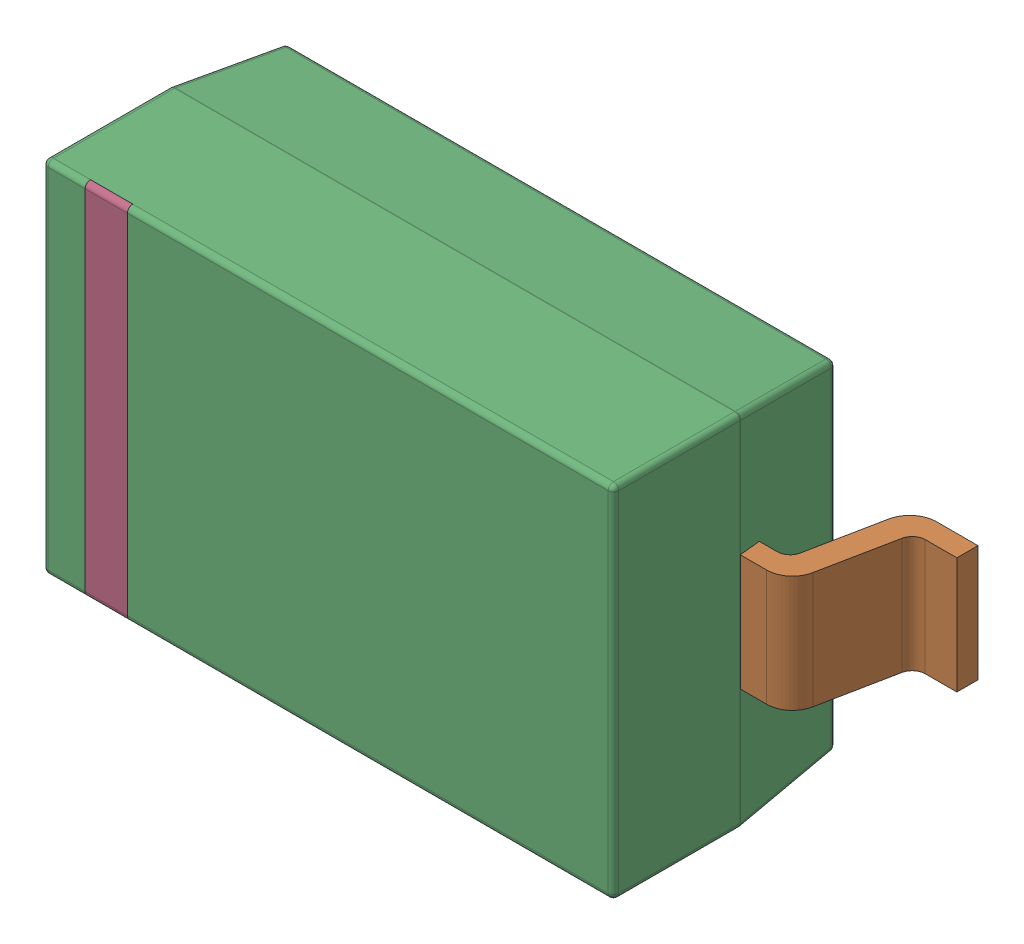
SolidWorks assembly D6, configuration Default. Lengths in mm.
Overall size (3.75 1.71 1.2).
5 component instances, 4 part files, 0 mates.
Components (placement in the parent):
- sod123_v4-1: sod123_v4 [Default] at (75.4701 4.8401 0) x (1 0 0) z (0 0 1) size (3.75 1.71 1.2)
  - pin-1: pin [Default] at (-0.675 -0.875 0) x (0 -1 0) z (0 0 1) size (0.55 0.55 0.6)
  - pin(Mirror)-1: pin(Mirror) [Default] at (0.675 -0.875 0) x (0 -1 0) z (0 0 -1) size (0.55 0.55 0.6)
  - icbody-1: icbody [Default] at origin size (2.71 1.71 1.11)
  - Component5-1: Component5 [Default] at origin size (0.2 1.7 0.02)
